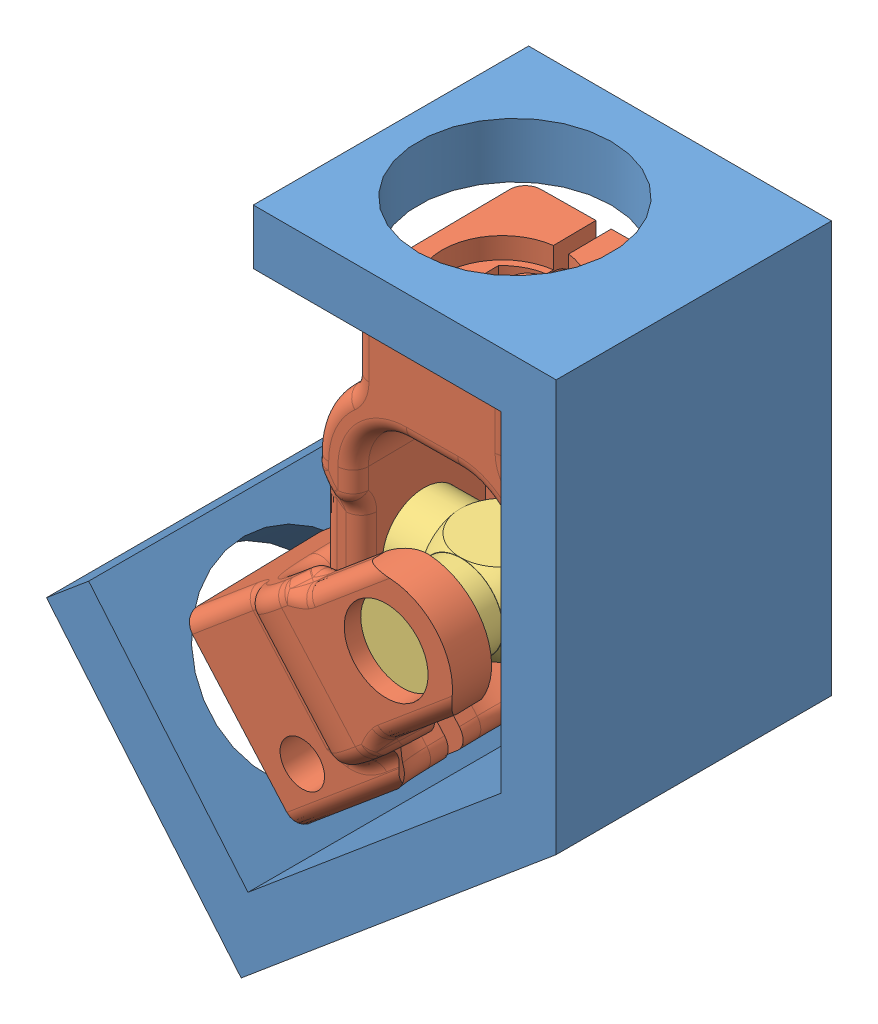
SolidWorks assembly juntauniversal, configuration Default. Lengths in mm.
Overall size (92.55 122.66 50).
4 component instances, 3 part files, 7 mates.
Components (placement in the parent):
- joint fix-1: joint fix [Default] at (-116.4326 58.5524 30.8166) size (92.55 122.66 50)
- User Library-Universal Joint_10755-1: User Library-Universal Joint_10755 [Default] at (-115.8056 -19.3093 55.8166) x (-0.766044 -0.642788 0) z (0.011289 -0.013453 0.999846) size (58.42 31.5 42.96)
- User Library-Universal Joint_10755-1-1: User Library-Universal Joint_10755-1 [Default] at (-96.2266 -2.8802 55.8015) x (0.999936 0 -0.01129) z (0.011289 -0.013453 0.999846) size (36.68 15.09 36.68)
- User Library-Universal Joint_10755-2: User Library-Universal Joint_10755 [Default] at (-96.2417 22.6785 55.8017) x (0 1 0) z (-0.999936 0 0.01129) size (58.42 31.5 42.96)
Mates (geometry in assembly coordinates):
- Concentric1: concentric anti-aligned: cylinder of User Library-Universal Joint_10755-1 through (-96.4689 -2.5915 34.34) axis (0.011289 -0.013453 0.999846) radius 7.5311; cylinder of User Library-Universal Joint_10755-1-1 through (-96.0196 -3.1269 74.1371) axis (-0.011289 0.013453 -0.999846) radius 7.493
- Distance2: distance = 3 mm aligned: plane of User Library-Universal Joint_10755-1-1 through (-96.0196 -3.1269 74.1371) normal (0.011289 -0.013453 0.999846); plane of User Library-Universal Joint_10755-1 through (-79.5599 -4.22 76.937) normal (0.011289 -0.013453 0.999846)
- Concentric2: concentric aligned: cylinder of joint fix-1 through (-131.858 -32.7789 55.8166) axis (-0.766044 -0.642788 0) radius 17.5; cylinder of User Library-Universal Joint_10755-1 through (-128.9297 -30.3217 55.8166) axis (-0.766044 -0.642788 0) radius 10.8902
- Coincident4: coincident anti-aligned: plane of joint fix-1 through (-146.3207 -15.5429 80.8166) normal (0.766044 0.642788 0); plane of User Library-Universal Joint_10755-1 through (-124.712 -41.2951 41.5222) normal (-0.766044 -0.642788 0)
- Concentric3: concentric anti-aligned: cylinder of User Library-Universal Joint_10755-1-1 through (-114.5638 -2.8802 56.0086) axis (0.999936 0 -0.01129) radius 7.493; cylinder of User Library-Universal Joint_10755-2 through (-74.7632 -2.8802 55.5592) axis (-0.999936 0 0.01129) radius 7.5311
- Distance3: distance = 3 mm aligned: plane of User Library-Universal Joint_10755-1-1 through (-114.5638 -2.8802 56.0086) normal (-0.999936 0 0.01129); plane of User Library-Universal Joint_10755-2 through (-117.692 -14.7865 44.6767) normal (-0.999936 0 0.01129)
- Parallel2: parallel aligned: plane of joint fix-1 through (-116.4326 58.5524 80.8166) normal (0 1 0); plane of User Library-Universal Joint_10755-2 through (-82.2739 43.6335 44.2768) normal (0 1 0)
